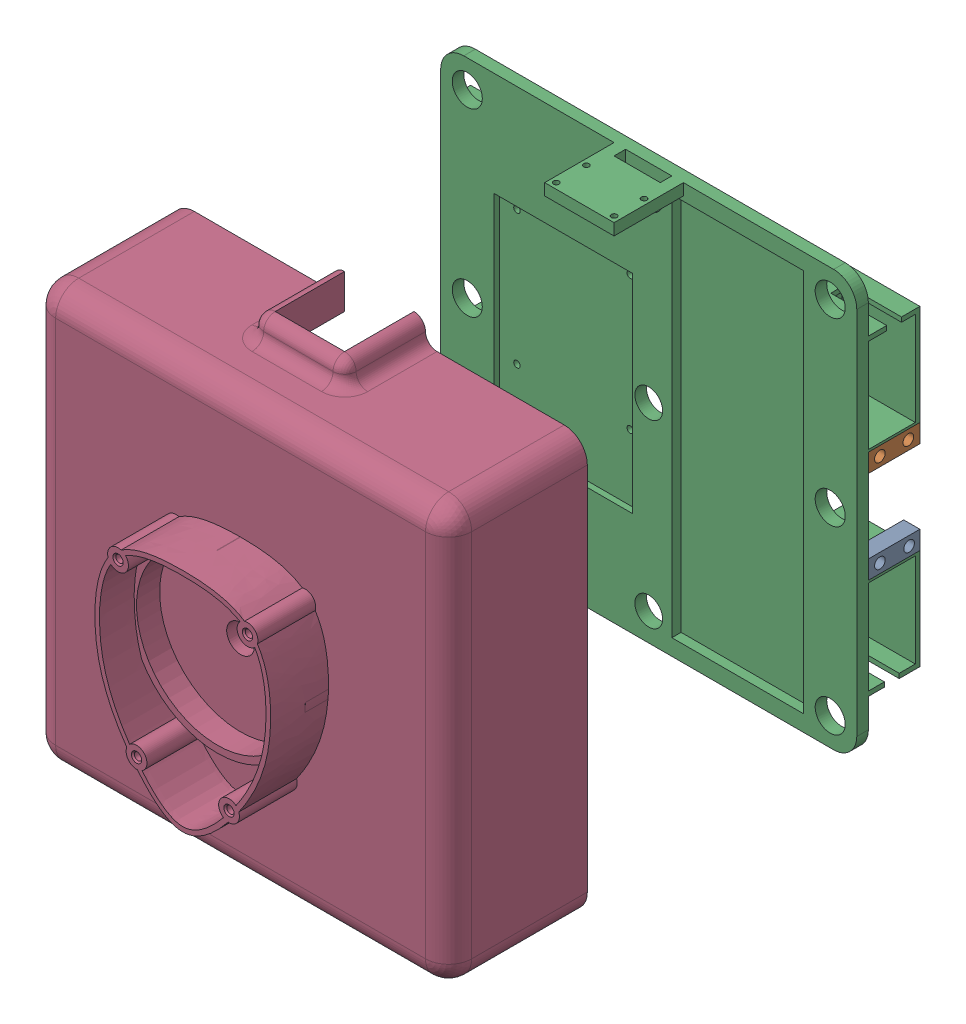
SolidWorks assembly STEVE Assembly V1, configuration Default. Lengths in mm.
Overall size (180 190 228.87).
2 component instances, 2 part files, 2 mates.
Components (placement in the parent):
- Main Board V1-1: Main Board V1 [Default] at (595.3189 849.0037 1309.7793) size (180 180 57.3)
- Top Shell V1-1: Top Shell V1 [Default] at (595.3189 849.0037 1431.3519) x (0 1 0) z (1 0 0) size (190 85 180)
Mates (geometry in assembly coordinates):
- Coincident2: coincident aligned: plane of Main Board V1-1 through (685.3189 939.0037 1314.7793) normal (1 0 0); plane of Top Shell V1-1 through (685.3189 759.0037 1491.3519) normal (1 0 0)
- Coincident3: coincident aligned: plane of Main Board V1-1 through (685.3189 939.0037 1314.7793) normal (0 1 0); plane of Top Shell V1-1 through (505.3189 939.0037 1491.3519) normal (0 1 0)
